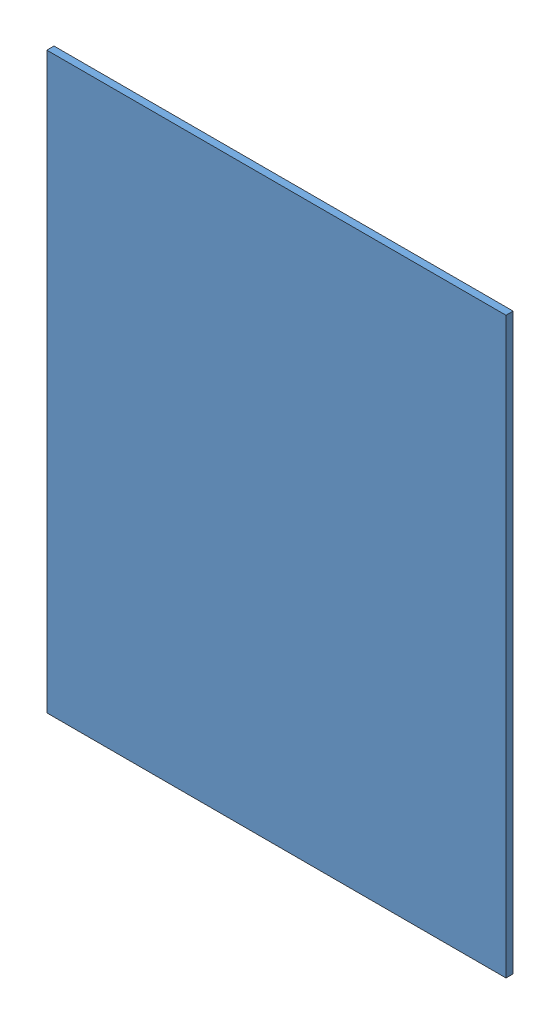
SolidWorks assembly Ensamblaje1, configuration Predeterminado. Lengths in mm.
Overall size (321.25 400 7.5).
3 component instances, 2 part files, 6 mates.
Components (placement in the parent):
- puerta-1: puerta [Predeterminado] at (-127.0731 141.1243 397.5) size (320 400 5)
- HInge_2-1: HInge_2 [Default] at (-185.3567 135.8752 397.5) x (0 0 -1) z (0 1 0) size (2.5 16.25 25)
- HInge_2-2: HInge_2 [Default] at (-185.3567 -139.1248 397.5) x (0 0 -1) z (0 1 0) size (2.5 16.25 25)
Mates (geometry in assembly coordinates):
- Coincidente1: coincident: plane of puerta-1 through (-127.0731 141.1243 397.5) normal (0 0 -1); plane of HInge_2-1 through (-185.3567 135.8752 397.5) normal (0 0 1)
- Coincidente2: coincident: line of puerta-1 through (-200.3567 185.8752 397.5) axis (0 -1 0); line of HInge_2-1 through (-200.3567 125.8752 397.5) axis (0 1 0)
- Distancia1: distance = 50 mm: line of HInge_2-1 through (-200.3567 135.8752 397.5) axis (1 0 0); line of puerta-1 through (119.6433 185.8752 397.5) axis (-1 0 0)
- Coincidente4: coincident: line of puerta-1 through (-200.3567 185.8752 397.5) axis (0 -1 0); line of HInge_2-2 through (-200.3567 -159.1248 397.5) axis (0 1 0)
- Coincidente5: coincident: plane of puerta-1 through (-127.0731 141.1243 397.5) normal (0 0 -1); plane of HInge_2-2 through (-185.3567 -139.1248 397.5) normal (0 0 1)
- Distancia2: distance = 50 mm: line of HInge_2-2 through (-185.3567 -164.1248 397.5) axis (-1 0 0); line of puerta-1 through (-200.3567 -214.1248 397.5) axis (1 0 0)
